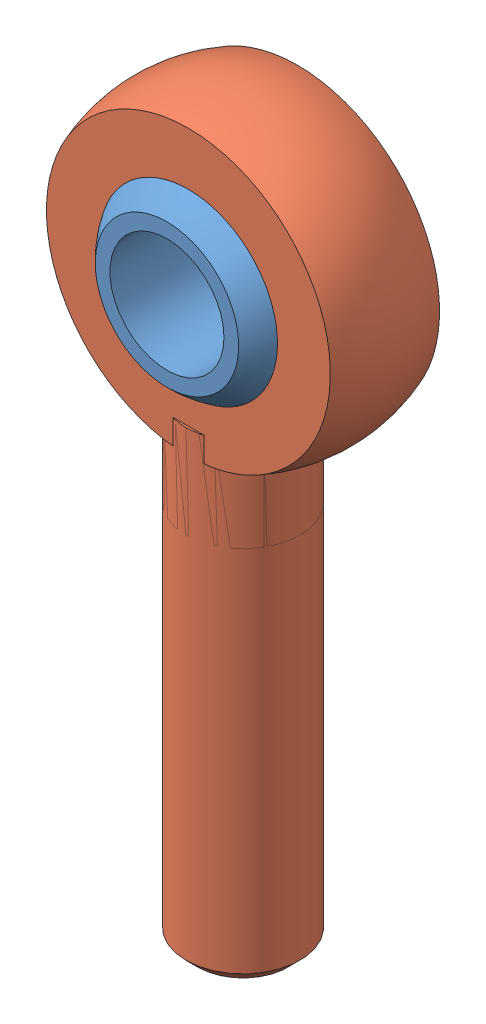
SolidWorks assembly RodEnd375-24L, configuration Default. Lengths in mm.
Overall size (25.4 61.93 22.2).
2 component instances, 2 part files, 1 mates.
Components (placement in the parent):
- RodEndBall375-1: RodEndBall375 [Default] at origin size (17.45 17.45 22.2)
- RodEndRace375-1: RodEndRace375 [Default] at origin size (25.4 61.93 9.53)
Mates (geometry in assembly coordinates):
- Coincident1: coincident: point of RodEndBall375-1; point of RodEndRace375-1
